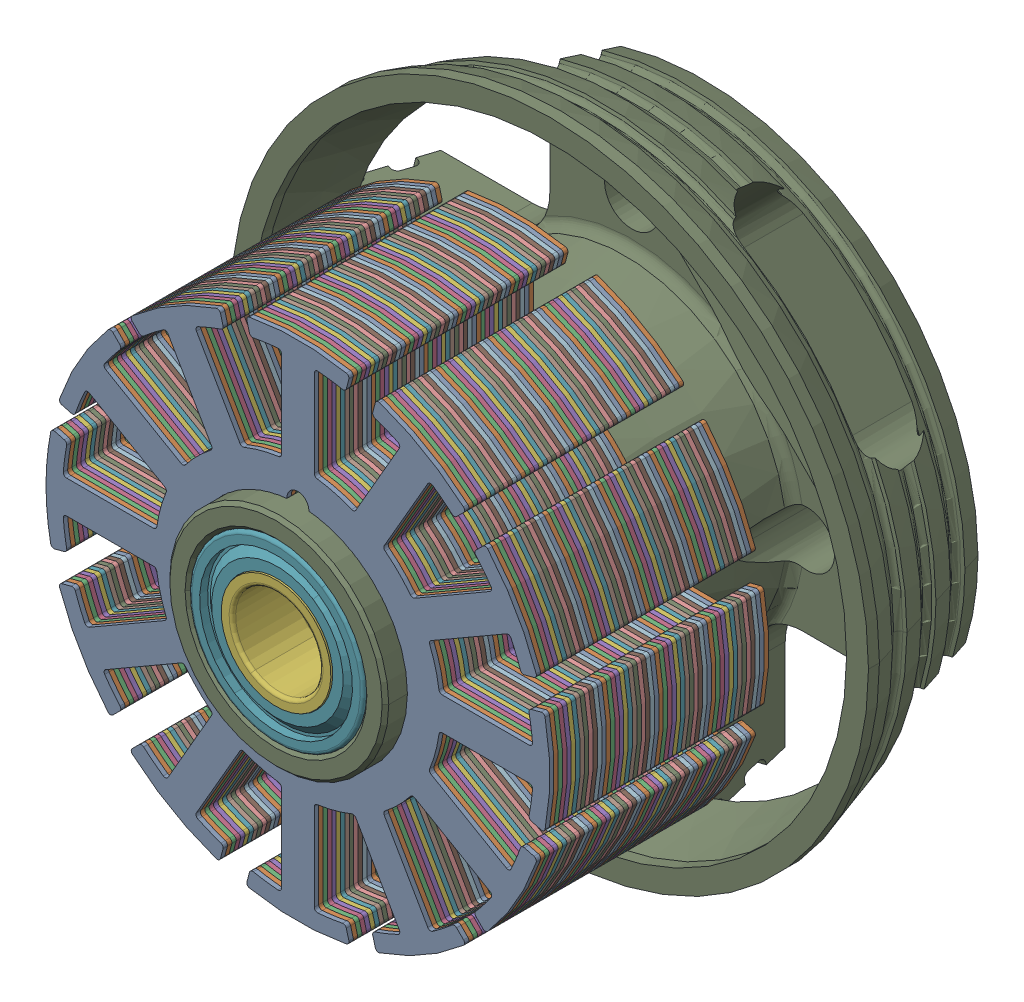
SolidWorks assembly 2310-Stator-Assem.STEP, configuration Default. Lengths in mm.
Overall size (29.1 29.1 19.5).
72 component instances, 8 part files, 0 mates.
Components (placement in the parent):
- 23x10x10mm-Stator.STEP-1: 23x10x10mm-Stator.STEP [Default] at (52.3253 8.3812 -27.0554) size (23 23 10)
  - 23x10x5mm-Stator.STEP-1: 23x10x5mm-Stator.STEP [Default] at (-16.2466 9.1923 4.328) size (23 23 5)
    - 23x10x1mm-Stator.STEP-1: 23x10x1mm-Stator.STEP [Default] at (-15.1244 2.7036 6.5442) size (23 23 1)
      - 23x10-Stator-Plate.STEP-1: 23x10-Stator-Plate.STEP [Default] at (-25.8459 0.0676 13.4926) size (23 23 0.2)
      - 23x10-Stator-Plate.STEP-2: 23x10-Stator-Plate.STEP [Default] at (-25.8459 0.0676 13.2926) size (23 23 0.2)
      - 23x10-Stator-Plate.STEP-3: 23x10-Stator-Plate.STEP [Default] at (-25.8459 0.0676 13.0926) size (23 23 0.2)
      - 23x10-Stator-Plate.STEP-4: 23x10-Stator-Plate.STEP [Default] at (-25.8459 0.0676 12.8926) size (23 23 0.2)
      - 23x10-Stator-Plate.STEP-5: 23x10-Stator-Plate.STEP [Default] at (-25.8459 0.0676 12.6926) size (23 23 0.2)
    - 23x10x1mm-Stator.STEP-2: 23x10x1mm-Stator.STEP [Default] at (-15.1244 2.7036 5.5442) size (23 23 1)
      - 23x10-Stator-Plate.STEP-1: 23x10-Stator-Plate.STEP [Default] at (-25.8459 0.0676 13.4926) size (23 23 0.2)
      - 23x10-Stator-Plate.STEP-2: 23x10-Stator-Plate.STEP [Default] at (-25.8459 0.0676 13.2926) size (23 23 0.2)
      - 23x10-Stator-Plate.STEP-3: 23x10-Stator-Plate.STEP [Default] at (-25.8459 0.0676 13.0926) size (23 23 0.2)
      - 23x10-Stator-Plate.STEP-4: 23x10-Stator-Plate.STEP [Default] at (-25.8459 0.0676 12.8926) size (23 23 0.2)
      - 23x10-Stator-Plate.STEP-5: 23x10-Stator-Plate.STEP [Default] at (-25.8459 0.0676 12.6926) size (23 23 0.2)
    - 23x10x1mm-Stator.STEP-3: 23x10x1mm-Stator.STEP [Default] at (-15.1244 2.7036 4.5442) size (23 23 1)
      - 23x10-Stator-Plate.STEP-1: 23x10-Stator-Plate.STEP [Default] at (-25.8459 0.0676 13.4926) size (23 23 0.2)
      - 23x10-Stator-Plate.STEP-2: 23x10-Stator-Plate.STEP [Default] at (-25.8459 0.0676 13.2926) size (23 23 0.2)
      - 23x10-Stator-Plate.STEP-3: 23x10-Stator-Plate.STEP [Default] at (-25.8459 0.0676 13.0926) size (23 23 0.2)
      - 23x10-Stator-Plate.STEP-4: 23x10-Stator-Plate.STEP [Default] at (-25.8459 0.0676 12.8926) size (23 23 0.2)
      - 23x10-Stator-Plate.STEP-5: 23x10-Stator-Plate.STEP [Default] at (-25.8459 0.0676 12.6926) size (23 23 0.2)
    - 23x10x1mm-Stator.STEP-4: 23x10x1mm-Stator.STEP [Default] at (-15.1244 2.7036 3.5442) size (23 23 1)
      - 23x10-Stator-Plate.STEP-1: 23x10-Stator-Plate.STEP [Default] at (-25.8459 0.0676 13.4926) size (23 23 0.2)
      - 23x10-Stator-Plate.STEP-2: 23x10-Stator-Plate.STEP [Default] at (-25.8459 0.0676 13.2926) size (23 23 0.2)
      - 23x10-Stator-Plate.STEP-3: 23x10-Stator-Plate.STEP [Default] at (-25.8459 0.0676 13.0926) size (23 23 0.2)
      - 23x10-Stator-Plate.STEP-4: 23x10-Stator-Plate.STEP [Default] at (-25.8459 0.0676 12.8926) size (23 23 0.2)
      - 23x10-Stator-Plate.STEP-5: 23x10-Stator-Plate.STEP [Default] at (-25.8459 0.0676 12.6926) size (23 23 0.2)
    - 23x10x1mm-Stator.STEP-5: 23x10x1mm-Stator.STEP [Default] at (-15.1244 2.7036 2.5442) size (23 23 1)
      - 23x10-Stator-Plate.STEP-1: 23x10-Stator-Plate.STEP [Default] at (-25.8459 0.0676 13.4926) size (23 23 0.2)
      - 23x10-Stator-Plate.STEP-2: 23x10-Stator-Plate.STEP [Default] at (-25.8459 0.0676 13.2926) size (23 23 0.2)
      - 23x10-Stator-Plate.STEP-3: 23x10-Stator-Plate.STEP [Default] at (-25.8459 0.0676 13.0926) size (23 23 0.2)
      - 23x10-Stator-Plate.STEP-4: 23x10-Stator-Plate.STEP [Default] at (-25.8459 0.0676 12.8926) size (23 23 0.2)
      - 23x10-Stator-Plate.STEP-5: 23x10-Stator-Plate.STEP [Default] at (-25.8459 0.0676 12.6926) size (23 23 0.2)
  - 23x10x5mm-Stator.STEP-2: 23x10x5mm-Stator.STEP [Default] at (-16.2466 9.1923 -0.672) size (23 23 5)
    - 23x10x1mm-Stator.STEP-1: 23x10x1mm-Stator.STEP [Default] at (-15.1244 2.7036 6.5442) size (23 23 1)
      - 23x10-Stator-Plate.STEP-1: 23x10-Stator-Plate.STEP [Default] at (-25.8459 0.0676 13.4926) size (23 23 0.2)
      - 23x10-Stator-Plate.STEP-2: 23x10-Stator-Plate.STEP [Default] at (-25.8459 0.0676 13.2926) size (23 23 0.2)
      - 23x10-Stator-Plate.STEP-3: 23x10-Stator-Plate.STEP [Default] at (-25.8459 0.0676 13.0926) size (23 23 0.2)
      - 23x10-Stator-Plate.STEP-4: 23x10-Stator-Plate.STEP [Default] at (-25.8459 0.0676 12.8926) size (23 23 0.2)
      - 23x10-Stator-Plate.STEP-5: 23x10-Stator-Plate.STEP [Default] at (-25.8459 0.0676 12.6926) size (23 23 0.2)
    - 23x10x1mm-Stator.STEP-2: 23x10x1mm-Stator.STEP [Default] at (-15.1244 2.7036 5.5442) size (23 23 1)
      - 23x10-Stator-Plate.STEP-1: 23x10-Stator-Plate.STEP [Default] at (-25.8459 0.0676 13.4926) size (23 23 0.2)
      - 23x10-Stator-Plate.STEP-2: 23x10-Stator-Plate.STEP [Default] at (-25.8459 0.0676 13.2926) size (23 23 0.2)
      - 23x10-Stator-Plate.STEP-3: 23x10-Stator-Plate.STEP [Default] at (-25.8459 0.0676 13.0926) size (23 23 0.2)
      - 23x10-Stator-Plate.STEP-4: 23x10-Stator-Plate.STEP [Default] at (-25.8459 0.0676 12.8926) size (23 23 0.2)
      - 23x10-Stator-Plate.STEP-5: 23x10-Stator-Plate.STEP [Default] at (-25.8459 0.0676 12.6926) size (23 23 0.2)
    - 23x10x1mm-Stator.STEP-3: 23x10x1mm-Stator.STEP [Default] at (-15.1244 2.7036 4.5442) size (23 23 1)
      - 23x10-Stator-Plate.STEP-1: 23x10-Stator-Plate.STEP [Default] at (-25.8459 0.0676 13.4926) size (23 23 0.2)
      - 23x10-Stator-Plate.STEP-2: 23x10-Stator-Plate.STEP [Default] at (-25.8459 0.0676 13.2926) size (23 23 0.2)
      - 23x10-Stator-Plate.STEP-3: 23x10-Stator-Plate.STEP [Default] at (-25.8459 0.0676 13.0926) size (23 23 0.2)
      - 23x10-Stator-Plate.STEP-4: 23x10-Stator-Plate.STEP [Default] at (-25.8459 0.0676 12.8926) size (23 23 0.2)
      - 23x10-Stator-Plate.STEP-5: 23x10-Stator-Plate.STEP [Default] at (-25.8459 0.0676 12.6926) size (23 23 0.2)
    - 23x10x1mm-Stator.STEP-4: 23x10x1mm-Stator.STEP [Default] at (-15.1244 2.7036 3.5442) size (23 23 1)
      - 23x10-Stator-Plate.STEP-1: 23x10-Stator-Plate.STEP [Default] at (-25.8459 0.0676 13.4926) size (23 23 0.2)
      - 23x10-Stator-Plate.STEP-2: 23x10-Stator-Plate.STEP [Default] at (-25.8459 0.0676 13.2926) size (23 23 0.2)
      - 23x10-Stator-Plate.STEP-3: 23x10-Stator-Plate.STEP [Default] at (-25.8459 0.0676 13.0926) size (23 23 0.2)
      - 23x10-Stator-Plate.STEP-4: 23x10-Stator-Plate.STEP [Default] at (-25.8459 0.0676 12.8926) size (23 23 0.2)
      - 23x10-Stator-Plate.STEP-5: 23x10-Stator-Plate.STEP [Default] at (-25.8459 0.0676 12.6926) size (23 23 0.2)
    - 23x10x1mm-Stator.STEP-5: 23x10x1mm-Stator.STEP [Default] at (-15.1244 2.7036 2.5442) size (23 23 1)
      - 23x10-Stator-Plate.STEP-1: 23x10-Stator-Plate.STEP [Default] at (-25.8459 0.0676 13.4926) size (23 23 0.2)
      - 23x10-Stator-Plate.STEP-2: 23x10-Stator-Plate.STEP [Default] at (-25.8459 0.0676 13.2926) size (23 23 0.2)
      - 23x10-Stator-Plate.STEP-3: 23x10-Stator-Plate.STEP [Default] at (-25.8459 0.0676 13.0926) size (23 23 0.2)
      - 23x10-Stator-Plate.STEP-4: 23x10-Stator-Plate.STEP [Default] at (-25.8459 0.0676 12.8926) size (23 23 0.2)
      - 23x10-Stator-Plate.STEP-5: 23x10-Stator-Plate.STEP [Default] at (-25.8459 0.0676 12.6926) size (23 23 0.2)
- 4x11x4-BRG.STEP-1: 4x11x4-BRG.STEP [Default] at (-4.8916 20.3447 -18.4846) x (0 0 1) z (-0.998854 -0.047866 0) size (3.99 11 11)
  - 694HZZ_SOLID_1-1.STEP-1: 694HZZ_SOLID_1-1.STEP [Default] at origin size (3.99 6.18 6.18)
  - 694HZZ_SOLID_2-1.STEP-1: 694HZZ_SOLID_2-1.STEP [Default] at origin size (3.99 11 11)
  - 694HZZ_SOLID_3-1.STEP-1: 694HZZ_SOLID_3-1.STEP [Default] at origin size (2.34 9.37 9.37)
- 4x8x3-BRG.STEP-1: 4x8x3-BRG.STEP [Default] at (-4.8916 20.3447 -2.9921) x (0 0 -1) z (0.838857 -0.544351 0) size (3 8 8)
  - SMR84ZZ_SOLID_1.STEP-1: SMR84ZZ_SOLID_1.STEP [Default] at origin size (3 5.01 5.01)
  - SMR84ZZ_SOLID_2.STEP-1: SMR84ZZ_SOLID_2.STEP [Default] at origin size (3 8 8)
  - SMR84ZZ_SOLID_3.STEP-1: SMR84ZZ_SOLID_3.STEP [Default] at origin size (1.76 7.4 7.4)
- 2310-Mount.STEP-1: 2310-Mount.STEP [Default] at (-4.8916 20.3447 -20.9907) size (29.1 29.1 19.5)
